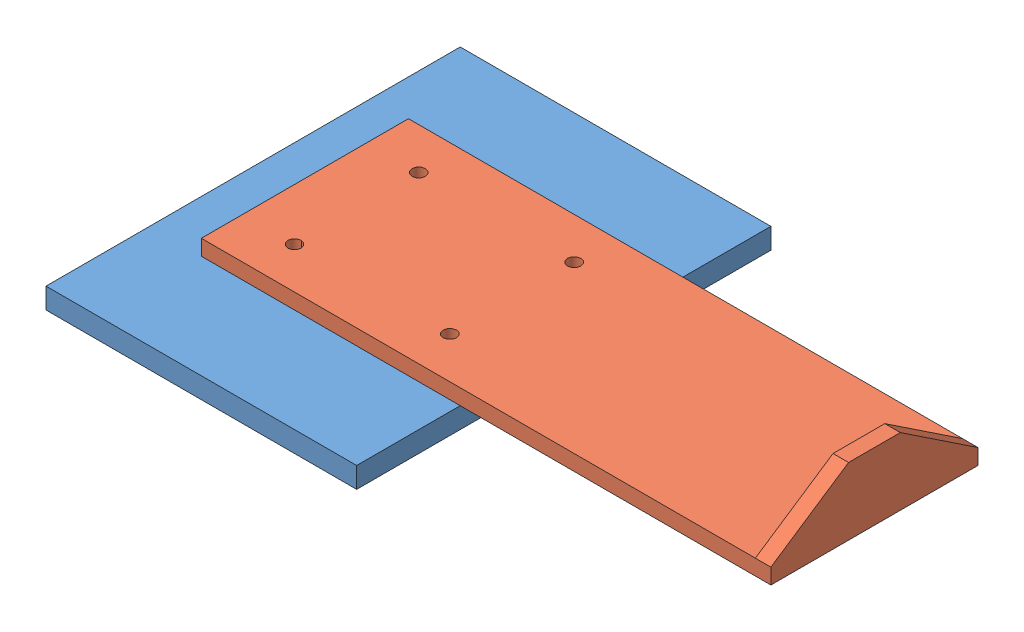
SolidWorks assembly Support Plate and Angle Bracket, configuration Default. Lengths in mm.
Overall size (600 85 400).
2 component instances, 2 part files, 3 mates.
Components (placement in the parent):
- Support Plate-1: Support Plate [Default] at origin size (300 20 400)
- Angle Bracket-1: Angle Bracket [Default] at (-100 15 0) size (550 65 200)
Mates (geometry in assembly coordinates):
- Concentric1: concentric: cylinder of Support Plate-1 through (-50 -20 -60) axis (0 1 0) radius 6.5; cylinder of Angle Bracket-1 through (-50 0 -60) axis (0 1 0) radius 6.5
- Concentric2: concentric: cylinder of Support Plate-1 through (-50 -20 60) axis (0 1 0) radius 6.5; cylinder of Angle Bracket-1 through (-50 0 60) axis (0 1 0) radius 6.5
- Coincident1: coincident anti-aligned: plane of Support Plate-1 through (-150 0 200) normal (0 1 0); plane of Angle Bracket-1 through (-100 0 -100) normal (0 -1 0)
